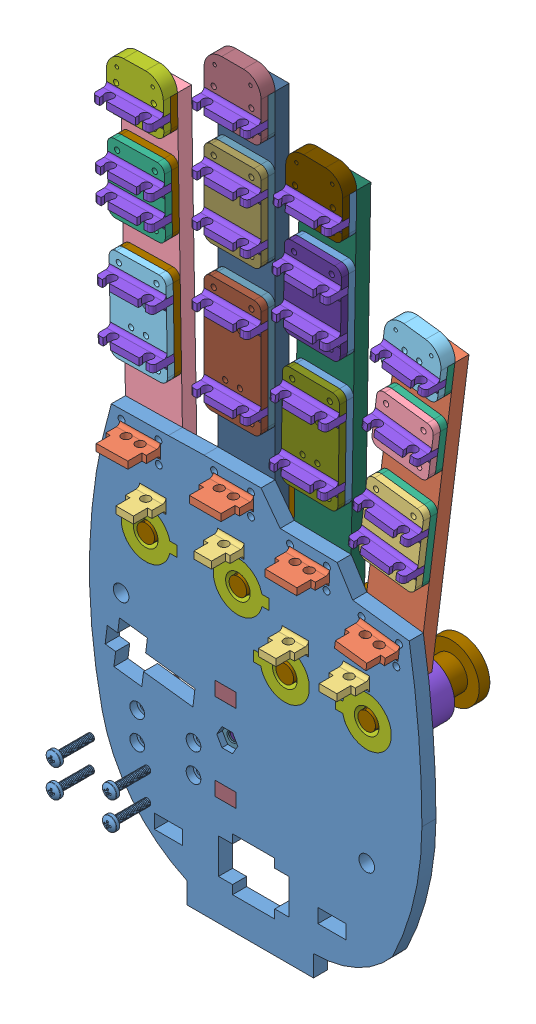
SolidWorks assembly palmUp_fingers_buttons_upPulley_servoBase, configuration Default. Lengths in mm.
Overall size (100.53 213.84 66.17).
198 component instances, 46 part files, 121 mates.
Components (placement in the parent):
- palmUp-1: palmUp [Default] at (29.1174 30.4931 80.2216) size (94.52 113.2 4)
- driverBaseFrame1-1: driverBaseFrame1 [Default] at (-2.9175 115.1932 80.2216) x (0.999847 0.017467 0) z (0.017467 -0.999847 0) size (11.5 12 4)
- driverBaseFrame1-2: driverBaseFrame1 [Default] at (23.5924 115.6931 80.2216) x (1 0 0) z (0 -1 0) size (11.5 12 4)
- driverBaseFrame1-3: driverBaseFrame1 [Default] at (45.1535 108.3901 80.2216) x (0.999848 -0.017452 0) z (-0.017452 -0.999848 0) size (11.5 12 4)
- driverBaseFrame1-4: driverBaseFrame1 [Default] at (65.1211 100.8452 80.2216) x (0.992117 -0.125312 0) z (-0.125312 -0.992117 0) size (11.5 12 4)
- driverBaseFrame2-1: driverBaseFrame2 [Default] at (-1948.2383 102.6443 -1374.6625) x (1 0 0) z (0 -1 0) size (7.5 12 4)
- driverBaseFrame2-2: driverBaseFrame2 [Default] at (1983.3157 100.6443 -1374.6625) x (-1 0 0) z (0 1 0) size (7.5 12 4)
- driverBaseFrame2-4: driverBaseFrame2 [Default] at (-1907.6963 87.8147 -1374.6625) x (1 0 0) z (0 -1 0) size (7.5 12 4)
- driverBaseFrame2-5: driverBaseFrame2 [Default] at (-1890.412 87.8147 -1374.6625) x (1 0 0) z (0 -1 0) size (7.5 12 4)
- index-1: index [Default] at (-52.494 173.2306 -0.0096) x (-0.999847 -0.017467 0) z (0 0 -1) size (16.2 99.16 12.01)
  - indexElastomer-1: indexElastomer [Default] at (-62.4059 -67.241 -80.2312) size (16.2 94.16 4)
  - indexPIP-1: indexPIP [Default] at (-62.4059 -42.8945 -84.2312) size (16.2 26.26 2)
  - indexMIP-1: indexMIP [Default] at (-62.4059 -8.6345 -84.2312) size (16.2 19.45 2)
  - indexDIP-1: indexDIP [Default] at (-62.4059 16.8205 -84.2312) size (16.2 14.95 4)
  - tubeDriver-6: tubeDriver [Default] at (-62.4059 20.8205 -80.2312) x (1 0 0) z (0 1 0) size (16.2 6 4)
  - tubeDriver-7: tubeDriver [Default] at (-62.4059 3.8205 -80.2312) x (1 0 0) z (0 1 0) size (16.2 6 4)
  - tubeDriver-8: tubeDriver [Default] at (-62.4059 -3.6345 -80.2312) x (1 0 0) z (0 1 0) size (16.2 6 4)
  - tubeDriver-9: tubeDriver [Default] at (-62.4059 -23.6345 -80.2312) x (1 0 0) z (0 1 0) size (16.2 6 4)
  - tubeDriver-10: tubeDriver [Default] at (-62.4059 -37.8945 -80.2312) x (1 0 0) z (0 1 0) size (16.2 6 4)
  - indexTube1-1: indexTube1 [Default] at (-49.2059 -21.6345 -86.4812) x (-0.964902 0 0.26261) z (0 -1 0) size (2.5 2.5 16.26) (hidden)
  - indexTube1-2: indexTube1 [Default] at (-59.4059 -21.6345 -86.4812) x (-0.775159 0 0.631766) z (0 -1 0) size (2.5 2.5 16.26) (hidden)
  - indexTube2-1: indexTube2 [Default] at (-49.2059 5.8205 -86.4812) x (0.360054 0 0.932932) z (0 -1 0) size (2.5 2.5 9.46) (hidden)
  - indexTube2-2: indexTube2 [Default] at (-59.4059 5.8205 -86.4812) x (-0.658969 0 -0.75217) z (0 -1 0) size (2.5 2.5 9.46) (hidden)
  - commonFingersTube-1: commonFingersTube [Default] at (-49.2059 22.8205 -86.4812) x (-0.856421 0 0.516277) z (0 -1 0) size (2.5 2.5 2) (hidden)
  - commonFingersTube-2: commonFingersTube [Default] at (-59.4059 22.8205 -86.4812) x (-0.999231 0 0.039215) z (0 -1 0) size (2.5 2.5 2) (hidden)
  - indexJointBase-1: indexJointBase [Default] at (-62.4059 -67.241 -82.2312) size (16.2 69.66 2)
- middle-1: middle [Default] at (34.8412 175.8995 -30.6566) size (16.2 113.14 12)
  - middleElastomer-1: middleElastomer [Default] at (-13.8237 -68.7065 106.8781) size (16.2 108.14 4)
  - middlePIP-1: middlePIP [Default] at (-13.8237 -44.2065 110.8781) size (16.2 33.21 2)
  - middleMIP-1: middleMIP [Default] at (-13.8237 -2.9965 110.8781) size (16.2 24.45 2)
  - middleDIP-1: middleDIP [Default] at (-5.7237 27.4535 110.8781) size (16.2 16.98 4)
  - tubeDriver-2: tubeDriver [Default] at (-13.8237 33.4535 110.8781) x (1 0 0) z (0 -1 0) size (16.2 6 4)
  - tubeDriver-3: tubeDriver [Default] at (-13.8237 16.4535 110.8781) x (1 0 0) z (0 -1 0) size (16.2 6 4)
  - tubeDriver-4: tubeDriver [Default] at (-13.8237 4.0035 110.8781) x (1 0 0) z (0 -1 0) size (16.2 6 4)
  - tubeDriver-5: tubeDriver [Default] at (-13.8237 -15.9965 110.8781) x (1 0 0) z (0 -1 0) size (16.2 6 4)
  - tubeDriver-6: tubeDriver [Default] at (-13.8237 -37.2065 110.8781) x (1 0 0) z (0 -1 0) size (16.2 6 4)
  - middleTube1-1: middleTube1 [Default] at (-10.8237 -39.2065 117.1281) x (1 0 0) z (0 1 0) size (2.5 2.5 23.21) (hidden)
  - middleTube1-2: middleTube1 [Default] at (-0.6237 -39.2065 117.1281) x (1 0 0) z (0 1 0) size (2.5 2.5 23.21) (hidden)
  - middleTube2-1: middleTube2 [Default] at (-10.8237 2.0035 117.1281) x (1 0 0) z (0 1 0) size (2.5 2.5 14.45) (hidden)
  - middleTube2-2: middleTube2 [Default] at (-0.6237 2.0035 117.1281) x (1 0 0) z (0 1 0) size (2.5 2.5 14.45) (hidden)
  - commonFingersTube-1: commonFingersTube [Default] at (-10.8237 31.4535 117.1281) x (1 0 0) z (0 1 0) size (2.5 2.5 2) (hidden)
  - commonFingersTube-2: commonFingersTube [Default] at (-0.6237 31.4535 117.1281) x (1 0 0) z (0 1 0) size (2.5 2.5 2) (hidden)
  - middleJointBase-1: middleJointBase [Default] at (-13.8237 -70.2065 110.8781) size (16.2 83.64 2)
- ring-1: ring [Default] at (23.5555 139.8292 -20.9472) x (-0.999848 0.017452 0) z (0 0 -1) size (16.2 107.96 12)
  - ringElastomer-1: ringElastomer [Default] at (-35.7683 -39.5573 -101.1688) size (16.2 102.96 4)
  - ringPIP-1: ringPIP [Default] at (-35.7683 -15.0573 -105.1688) size (16.2 29.14 2)
  - ringMIP-1: ringMIP [Default] at (-35.7683 22.0827 -105.1688) size (16.2 23.53 2)
  - ringDIP-1: ringDIP [Default] at (-19.5683 51.6077 -101.1688) x (-1 0 0) z (0 0 -1) size (16.2 16.8 4)
  - tubeDriver-6: tubeDriver [Default] at (-35.7683 55.6077 -101.1688) x (1 0 0) z (0 1 0) size (16.2 6 4)
  - tubeDriver-7: tubeDriver [Default] at (-35.7683 38.6077 -101.1688) x (1 0 0) z (0 1 0) size (16.2 6 4)
  - tubeDriver-8: tubeDriver [Default] at (-35.7683 27.0827 -101.1688) x (1 0 0) z (0 1 0) size (16.2 6 4)
  - tubeDriver-9: tubeDriver [Default] at (-35.7683 7.0827 -101.1688) x (1 0 0) z (0 1 0) size (16.2 6 4)
  - tubeDriver-10: tubeDriver [Default] at (-35.7683 -10.0573 -101.1688) x (1 0 0) z (0 1 0) size (16.2 6 4)
  - ringTube1-1: ringTube1 [Default] at (-22.5683 9.0827 -107.4188) x (1 0 0) z (0 -1 0) size (2.5 2.5 19.14) (hidden)
  - ringTube1-2: ringTube1 [Default] at (-32.7683 9.0827 -107.4188) x (1 0 0) z (0 -1 0) size (2.5 2.5 19.14) (hidden)
  - ringTube2-1: ringTube2 [Default] at (-22.5683 40.6077 -107.4188) x (1 0 0) z (0 -1 0) size (2.5 2.5 13.53) (hidden)
  - ringTube2-2: ringTube2 [Default] at (-32.7683 40.6077 -107.4188) x (1 0 0) z (0 -1 0) size (2.5 2.5 13.53) (hidden)
  - commonFingersTube-1: commonFingersTube [Default] at (-22.5683 57.6077 -107.4188) x (1 0 0) z (0 -1 0) size (2.5 2.5 2) (hidden)
  - commonFingersTube-2: commonFingersTube [Default] at (-32.7683 57.6077 -107.4188) x (-0.448476 0 -0.893795) z (0 -1 0) size (2.5 2.5 2) (hidden)
  - ringJointBase-1: ringJointBase [Default] at (-35.7683 -41.0573 -103.1688) size (16.2 78.46 2)
- pinky-1: pinky [Default] at (76.9532 164.3008 -0.0182) x (0.992117 -0.125312 0) z (0 0 1) size (16.2 89.09 12)
  - pinkyElastomer-1: pinkyElastomer [Default] at (-6.1366 -72.9381 76.2397) size (16.2 84.09 4)
  - pinkyPIP-1: pinkyPIP [Default] at (-6.1366 -48.4381 80.2397) size (16.2 21.74 2)
  - pinkyMIP-1: pinkyMIP [Default] at (-6.1366 -18.6981 80.2397) size (16.2 14.64 2)
  - pinkyDIP-1: pinkyDIP [Default] at (-6.1366 1.9469 80.2397) size (16.2 14.21 4)
  - tubeDriver-5: tubeDriver [Default] at (-6.1366 7.9469 80.2397) x (1 0 0) z (0 -1 0) size (16.2 6 4)
  - tubeDriver-7: tubeDriver [Default] at (-6.1366 -31.6981 80.2397) x (1 0 0) z (0 -1 0) size (16.2 6 4)
  - tubeDriver-8: tubeDriver [Default] at (-6.1366 -41.4381 80.2397) x (1 0 0) z (0 -1 0) size (16.2 6 4)
  - pinkyTube1-1: pinkyTube1 [Default] at (-3.1366 -43.4381 86.4897) x (1 0 0) z (0 1 0) size (2.5 2.5 11.74) (hidden)
  - pinkyTube1-2: pinkyTube1 [Default] at (7.0634 -43.4381 86.4897) x (1 0 0) z (0 1 0) size (2.5 2.5 11.74) (hidden)
  - tubeDriver-10: tubeDriver [Default] at (-6.1366 -10.3756 80.2397) x (1 0 0) z (0 -1 0) size (16.2 6 4)
  - commonFingersTube-1: commonFingersTube [Default] at (-3.1366 5.9469 86.4897) x (1 0 0) z (0 1 0) size (2.5 2.5 2) (hidden)
  - commonFingersTube-2: commonFingersTube [Default] at (7.0634 5.9469 86.4897) x (1 0 0) z (0 1 0) size (2.5 2.5 2) (hidden)
  - pinkyJointBase-1: pinkyJointBase [Default] at (-6.1366 -74.4381 80.2397) size (16.2 59.59 2)
  - commonFingersTube-3: commonFingersTube [Default] at (-3.1366 -12.3756 86.4897) x (1 0 0) z (0 1 0) size (2.5 2.5 2) (hidden)
  - commonFingersTube-4: commonFingersTube [Default] at (7.0634 -12.3756 86.4897) x (1 0 0) z (0 1 0) size (2.5 2.5 2) (hidden)
- buttonBase-1: buttonBase [Default] at (67.2648 77.3147 84.2216) x (0 -1 0) z (0 0 -1) size (16 16.84 9)
- buttonBase-2: buttonBase [Default] at (43.9805 77.3147 84.2216) x (0 -1 0) z (0 0 -1) size (16 16.84 9)
- buttonBase-3: buttonBase [Default] at (30.6388 92.1443 84.2216) x (0 1 0) z (0 0 -1) size (16 16.84 9)
- buttonBase-4: buttonBase [Default] at (4.4385 92.1443 84.2216) x (0 1 0) z (0 0 -1) size (16 16.84 9)
- buttonFrame-1: buttonFrame [Default] at (67.2648 77.3147 67.2216) x (-0.367754 -0.929923 0) z (0 0 1) size (16 16 8)
- buttonFrame-2: buttonFrame [Default] at (43.9805 77.3147 67.2216) x (-0.367754 -0.929923 0) z (0 0 1) size (16 16 8)
- buttonFrame-3: buttonFrame [Default] at (4.4385 92.1443 67.2216) x (-0.366273 -0.930508 0) z (0 0 1) size (16 16 8)
- buttonFrame-4: buttonFrame [Default] at (30.6388 92.1443 67.2216) x (-0.366273 -0.930508 0) z (0 0 1) size (16 16 8)
- buttonAxle-1: buttonAxle [Default] at (67.2648 77.3147 57.2216) size (16 16 27)
- buttonAxle-2: buttonAxle [Default] at (4.4385 92.1443 57.2216) size (16 16 27)
- buttonAxle-3: buttonAxle [Default] at (43.9805 77.3147 57.2216) x (-1 0 0) z (0 0 1) size (16 16 27)
- buttonAxle-4: buttonAxle [Default] at (30.6388 92.1443 57.2216) x (-1 0 0) z (0 0 1) size (16 16 27)
- parallel pin hardened_din-1: parallel pin hardened_din [Parallel Pin ISO 8734 - 2 x 14 - A - St] at (67.5898 69.8147 71.2178) x (0 1 0) z (-0.989175 0 -0.14674) size (14 2 2)
- parallel pin hardened_din-2: parallel pin hardened_din [Parallel Pin ISO 8734 - 2 x 14 - A - St] at (43.6555 69.8147 71.2178) x (0 1 0) z (-0.930242 0 0.366947) size (14 2 2)
- parallel pin hardened_din-3: parallel pin hardened_din [Parallel Pin ISO 8734 - 2 x 14 - A - St] at (4.7635 98.6443 71.2178) x (0 -1 0) z (0 0 1) size (14 2 2)
- parallel pin hardened_din-4: parallel pin hardened_din [Parallel Pin ISO 8734 - 2 x 14 - A - St] at (30.3138 98.6443 71.2178) x (0 -1 0) z (-0.297916 0 0.954592) size (14 2 2)
- Assem1-1: Assem1 [Default] at (68.1098 77.3321 69.8525) x (0.982823 0 0.184551) z (0 -1 0) size (9.07 23.24 9)
  - Spring Part-1: Spring Part [Default] at origin size (9 1 4.5)
  - Spring Part-7: Spring Part [Default] at (-0.0474 0.6138 0) x (0.988155 0.15346 0) z (0 0 -1) size (9 1 4.5)
  - Spring Part-8: Spring Part [Default] at (-0.0474 1.8415 0) x (0.988155 -0.15346 0) z (0 0 1) size (9 1 4.5)
  - Spring Part-9: Spring Part [Default] at (-0.0474 3.0692 0) x (0.988155 0.15346 0) z (0 0 -1) size (9 1 4.5)
  - Spring Part-10: Spring Part [Default] at (-0.0474 4.2969 0) x (0.988155 -0.15346 0) z (0 0 1) size (9 1 4.5)
  - Spring Part-11: Spring Part [Default] at (-0.0474 5.5246 0) x (0.988155 0.15346 0) z (0 0 -1) size (9 1 4.5)
  - Spring Part-12: Spring Part [Default] at (-0.0474 6.7522 0) x (0.988155 -0.15346 0) z (0 0 1) size (9 1 4.5) (hidden)
  - Spring Part-13: Spring Part [Default] at (-0.0474 7.9799 0) x (0.988155 0.15346 0) z (0 0 -1) size (9 1 4.5) (hidden)
  - Spring Part-14: Spring Part [Default] at (-0.0474 9.2076 0) x (0.988155 -0.15346 0) z (0 0 1) size (9 1 4.5) (hidden)
  - Spring Part-15: Spring Part [Default] at (-0.0474 10.4353 0) x (0.988155 0.15346 0) z (0 0 -1) size (9 1 4.5) (hidden)
  - Spring Part-16: Spring Part [Default] at (-0.0474 11.663 0) x (0.988155 -0.15346 0) z (0 0 1) size (9 1 4.5) (hidden)
  - Spring Part-17: Spring Part [Default] at (-0.0474 12.8906 0) x (0.988155 0.15346 0) z (0 0 -1) size (9 1 4.5) (hidden)
  - Spring Part-18: Spring Part [Default] at (-0.0474 14.1183 0) x (0.988155 -0.15346 0) z (0 0 1) size (9 1 4.5) (hidden)
  - Spring Part-19: Spring Part [Default] at (-0.0474 15.346 0) x (0.988155 0.15346 0) z (0 0 -1) size (9 1 4.5) (hidden)
  - Spring Part-20: Spring Part [Default] at (-0.0474 16.5737 0) x (0.988155 -0.15346 0) z (0 0 1) size (9 1 4.5) (hidden)
  - Spring Part-21: Spring Part [Default] at (-0.0474 17.8013 0) x (0.988155 0.15346 0) z (0 0 -1) size (9 1 4.5) (hidden)
  - Spring Part-22: Spring Part [Default] at (-0.0474 19.029 0) x (0.988155 -0.15346 0) z (0 0 1) size (9 1 4.5) (hidden)
  - Spring Part-23: Spring Part [Default] at (-0.0474 20.2567 0) x (0.988155 0.15346 0) z (0 0 -1) size (9 1 4.5) (hidden)
  - Spring Part-24: Spring Part [Default] at (-0.0474 21.4844 0) x (0.988155 -0.15346 0) z (0 0 1) size (9 1 4.5) (hidden)
  - Spring Part-25: Spring Part [Default] at (0 22.0982 0) x (1 0 0) z (0 0 -1) size (9 1 4.5) (hidden)
- Assem1-2: Assem1 [Default] at (43.2323 76.9505 75.7945) x (0.961864 0.191525 0.195284) z (-0.195284 0.980747 0) size (9.07 23.24 9)
  - Spring Part-1: Spring Part [Default] at origin size (9 1 4.5)
  - Spring Part-7: Spring Part [Default] at (-0.0474 0.6138 0) x (0.988155 0.15346 0) z (0 0 -1) size (9 1 4.5)
  - Spring Part-8: Spring Part [Default] at (-0.0474 1.8415 0) x (0.988155 -0.15346 0) z (0 0 1) size (9 1 4.5)
  - Spring Part-9: Spring Part [Default] at (-0.0474 3.0692 0) x (0.988155 0.15346 0) z (0 0 -1) size (9 1 4.5)
  - Spring Part-10: Spring Part [Default] at (-0.0474 4.2969 0) x (0.988155 -0.15346 0) z (0 0 1) size (9 1 4.5)
  - Spring Part-11: Spring Part [Default] at (-0.0474 5.5246 0) x (0.988155 0.15346 0) z (0 0 -1) size (9 1 4.5)
  - Spring Part-12: Spring Part [Default] at (-0.0474 6.7522 0) x (0.988155 -0.15346 0) z (0 0 1) size (9 1 4.5) (hidden)
  - Spring Part-13: Spring Part [Default] at (-0.0474 7.9799 0) x (0.988155 0.15346 0) z (0 0 -1) size (9 1 4.5) (hidden)
  - Spring Part-14: Spring Part [Default] at (-0.0474 9.2076 0) x (0.988155 -0.15346 0) z (0 0 1) size (9 1 4.5) (hidden)
  - Spring Part-15: Spring Part [Default] at (-0.0474 10.4353 0) x (0.988155 0.15346 0) z (0 0 -1) size (9 1 4.5) (hidden)
  - Spring Part-16: Spring Part [Default] at (-0.0474 11.663 0) x (0.988155 -0.15346 0) z (0 0 1) size (9 1 4.5) (hidden)
  - Spring Part-17: Spring Part [Default] at (-0.0474 12.8906 0) x (0.988155 0.15346 0) z (0 0 -1) size (9 1 4.5) (hidden)
  - Spring Part-18: Spring Part [Default] at (-0.0474 14.1183 0) x (0.988155 -0.15346 0) z (0 0 1) size (9 1 4.5) (hidden)
  - Spring Part-19: Spring Part [Default] at (-0.0474 15.346 0) x (0.988155 0.15346 0) z (0 0 -1) size (9 1 4.5) (hidden)
  - Spring Part-20: Spring Part [Default] at (-0.0474 16.5737 0) x (0.988155 -0.15346 0) z (0 0 1) size (9 1 4.5) (hidden)
  - Spring Part-21: Spring Part [Default] at (-0.0474 17.8013 0) x (0.988155 0.15346 0) z (0 0 -1) size (9 1 4.5) (hidden)
  - Spring Part-22: Spring Part [Default] at (-0.0474 19.029 0) x (0.988155 -0.15346 0) z (0 0 1) size (9 1 4.5) (hidden)
  - Spring Part-23: Spring Part [Default] at (-0.0474 20.2567 0) x (0.988155 0.15346 0) z (0 0 -1) size (9 1 4.5) (hidden)
  - Spring Part-24: Spring Part [Default] at (-0.0474 21.4844 0) x (0.988155 -0.15346 0) z (0 0 1) size (9 1 4.5) (hidden)
  - Spring Part-25: Spring Part [Default] at (0 22.0982 0) x (1 0 0) z (0 0 -1) size (9 1 4.5) (hidden)
- Assem1-3: Assem1 [Default] at (30.4884 91.6348 76.0217) x (1 0 0) z (0 1 0) size (9.07 23.24 9)
  - Spring Part-1: Spring Part [Default] at origin size (9 1 4.5)
  - Spring Part-7: Spring Part [Default] at (-0.0474 0.6138 0) x (0.988155 0.15346 0) z (0 0 -1) size (9 1 4.5)
  - Spring Part-8: Spring Part [Default] at (-0.0474 1.8415 0) x (0.988155 -0.15346 0) z (0 0 1) size (9 1 4.5)
  - Spring Part-9: Spring Part [Default] at (-0.0474 3.0692 0) x (0.988155 0.15346 0) z (0 0 -1) size (9 1 4.5)
  - Spring Part-10: Spring Part [Default] at (-0.0474 4.2969 0) x (0.988155 -0.15346 0) z (0 0 1) size (9 1 4.5)
  - Spring Part-11: Spring Part [Default] at (-0.0474 5.5246 0) x (0.988155 0.15346 0) z (0 0 -1) size (9 1 4.5)
  - Spring Part-12: Spring Part [Default] at (-0.0474 6.7522 0) x (0.988155 -0.15346 0) z (0 0 1) size (9 1 4.5) (hidden)
  - Spring Part-13: Spring Part [Default] at (-0.0474 7.9799 0) x (0.988155 0.15346 0) z (0 0 -1) size (9 1 4.5) (hidden)
  - Spring Part-14: Spring Part [Default] at (-0.0474 9.2076 0) x (0.988155 -0.15346 0) z (0 0 1) size (9 1 4.5) (hidden)
  - Spring Part-15: Spring Part [Default] at (-0.0474 10.4353 0) x (0.988155 0.15346 0) z (0 0 -1) size (9 1 4.5) (hidden)
  - Spring Part-16: Spring Part [Default] at (-0.0474 11.663 0) x (0.988155 -0.15346 0) z (0 0 1) size (9 1 4.5) (hidden)
  - Spring Part-17: Spring Part [Default] at (-0.0474 12.8906 0) x (0.988155 0.15346 0) z (0 0 -1) size (9 1 4.5) (hidden)
  - Spring Part-18: Spring Part [Default] at (-0.0474 14.1183 0) x (0.988155 -0.15346 0) z (0 0 1) size (9 1 4.5) (hidden)
  - Spring Part-19: Spring Part [Default] at (-0.0474 15.346 0) x (0.988155 0.15346 0) z (0 0 -1) size (9 1 4.5) (hidden)
  - Spring Part-20: Spring Part [Default] at (-0.0474 16.5737 0) x (0.988155 -0.15346 0) z (0 0 1) size (9 1 4.5) (hidden)
  - Spring Part-21: Spring Part [Default] at (-0.0474 17.8013 0) x (0.988155 0.15346 0) z (0 0 -1) size (9 1 4.5) (hidden)
  - Spring Part-22: Spring Part [Default] at (-0.0474 19.029 0) x (0.988155 -0.15346 0) z (0 0 1) size (9 1 4.5) (hidden)
  - Spring Part-23: Spring Part [Default] at (-0.0474 20.2567 0) x (0.988155 0.15346 0) z (0 0 -1) size (9 1 4.5) (hidden)
  - Spring Part-24: Spring Part [Default] at (-0.0474 21.4844 0) x (0.988155 -0.15346 0) z (0 0 1) size (9 1 4.5) (hidden)
  - Spring Part-25: Spring Part [Default] at (0 22.0982 0) x (1 0 0) z (0 0 -1) size (9 1 4.5) (hidden)
- Assem1-4: Assem1 [Default] at (3.643 90.6443 75.9726) x (1 0 0) z (0 1 0) size (9.07 23.24 9)
  - Spring Part-1: Spring Part [Default] at origin size (9 1 4.5)
  - Spring Part-7: Spring Part [Default] at (-0.0474 0.6138 0) x (0.988155 0.15346 0) z (0 0 -1) size (9 1 4.5)
  - Spring Part-8: Spring Part [Default] at (-0.0474 1.8415 0) x (0.988155 -0.15346 0) z (0 0 1) size (9 1 4.5)
  - Spring Part-9: Spring Part [Default] at (-0.0474 3.0692 0) x (0.988155 0.15346 0) z (0 0 -1) size (9 1 4.5)
  - Spring Part-10: Spring Part [Default] at (-0.0474 4.2969 0) x (0.988155 -0.15346 0) z (0 0 1) size (9 1 4.5)
  - Spring Part-11: Spring Part [Default] at (-0.0474 5.5246 0) x (0.988155 0.15346 0) z (0 0 -1) size (9 1 4.5)
  - Spring Part-12: Spring Part [Default] at (-0.0474 6.7522 0) x (0.988155 -0.15346 0) z (0 0 1) size (9 1 4.5) (hidden)
  - Spring Part-13: Spring Part [Default] at (-0.0474 7.9799 0) x (0.988155 0.15346 0) z (0 0 -1) size (9 1 4.5) (hidden)
  - Spring Part-14: Spring Part [Default] at (-0.0474 9.2076 0) x (0.988155 -0.15346 0) z (0 0 1) size (9 1 4.5) (hidden)
  - Spring Part-15: Spring Part [Default] at (-0.0474 10.4353 0) x (0.988155 0.15346 0) z (0 0 -1) size (9 1 4.5) (hidden)
  - Spring Part-16: Spring Part [Default] at (-0.0474 11.663 0) x (0.988155 -0.15346 0) z (0 0 1) size (9 1 4.5) (hidden)
  - Spring Part-17: Spring Part [Default] at (-0.0474 12.8906 0) x (0.988155 0.15346 0) z (0 0 -1) size (9 1 4.5) (hidden)
  - Spring Part-18: Spring Part [Default] at (-0.0474 14.1183 0) x (0.988155 -0.15346 0) z (0 0 1) size (9 1 4.5) (hidden)
  - Spring Part-19: Spring Part [Default] at (-0.0474 15.346 0) x (0.988155 0.15346 0) z (0 0 -1) size (9 1 4.5) (hidden)
  - Spring Part-20: Spring Part [Default] at (-0.0474 16.5737 0) x (0.988155 -0.15346 0) z (0 0 1) size (9 1 4.5) (hidden)
  - Spring Part-21: Spring Part [Default] at (-0.0474 17.8013 0) x (0.988155 0.15346 0) z (0 0 -1) size (9 1 4.5) (hidden)
  - Spring Part-22: Spring Part [Default] at (-0.0474 19.029 0) x (0.988155 -0.15346 0) z (0 0 1) size (9 1 4.5) (hidden)
  - Spring Part-23: Spring Part [Default] at (-0.0474 20.2567 0) x (0.988155 0.15346 0) z (0 0 -1) size (9 1 4.5) (hidden)
  - Spring Part-24: Spring Part [Default] at (-0.0474 21.4844 0) x (0.988155 -0.15346 0) z (0 0 1) size (9 1 4.5) (hidden)
  - Spring Part-25: Spring Part [Default] at (0 22.0982 0) x (1 0 0) z (0 0 -1) size (9 1 4.5) (hidden)
- SupportPulleyPalmUpAssem-1: SupportPulleyPalmUpAssem [Default] at (18.0404 39.4745 49.5054) size (10 28.63 11.6)
  - supportPulleyPalmUp2-1: supportPulleyPalmUp2 [Default] at (10.0404 13.9256 23.1162) size (7.5 28.63 2)
  - supportPulleyPalmUp-1: supportPulleyPalmUp [Default] at (12.0404 26.3656 34.7162) x (-1 0 0) z (0 -1 0) size (10 11.6 4)
  - supportPulleyPalmUp-2: supportPulleyPalmUp [Default] at (12.0404 1.7356 34.7162) x (-1 0 0) z (0 -1 0) size (10 11.6 4)
- hex nut style 1 gradeab_din-1: hex nut style 1 gradeab_din [Hexagon Nut ISO 4032 - M3 - D - S] at (27.442 52.7975 82.6216) x (0 1 0) z (0 0 1) size (5.5 6.35 2.4)
- plain washer 6902 type abc_din-1: plain washer 6902 type abc_din [DIN 6902-C3.2] at (28.0808 53.4001 80.2216) x (0 0 -1) z (0.195239 0.980756 0) size (0.8 7 7)
- pulley-1: pulley [Default] at (28.0808 53.4001 75.4216) x (0.991013 -0.133768 0) z (0 0 1) size (12 12 4)
- plain washer 6902 type abc_din-2: plain washer 6902 type abc_din [DIN 6902-C3.2] at (28.0808 53.4001 75.4216) x (0 0 -1) z (0.978291 0.207235 0) size (0.8 7 7)
- socket head cap screw 4762_din-1: socket head cap screw 4762_din [ISO 4762 M3 x 10 --- 10S] at (28.0808 53.4001 69.6216) x (0 0 1) z (-0.999894 -0.01457 0) size (13 5.5 5.5)
- baseHerkulex-1: baseHerkulex [Default] at (-4.9352 30.4931 54.2216) size (31 58.5 17.5)
- pan head cross recess screw_din-1: pan head cross recess screw_din [ISO 7045 - M2 x 10 - Z --- 10S] at (18.0174 47.3687 108.8216) x (0 0 -1) z (0.086476 0.996254 0) size (11.57 4 4)
- pan head cross recess screw_din-2: pan head cross recess screw_din [ISO 7045 - M2 x 10 - Z --- 10S] at (18.0174 39.3687 108.8216) x (0 0 -1) z (-0.029913 -0.999553 0) size (11.57 4 4)
- pan head cross recess screw_din-3: pan head cross recess screw_din [ISO 7045 - M2 x 10 - Z --- 10S] at (2.0174 39.3687 108.8216) x (0 0 -1) z (1 0 0) size (11.57 4 4)
- pan head cross recess screw_din-4: pan head cross recess screw_din [ISO 7045 - M2 x 10 - Z --- 10S] at (2.0174 47.3687 108.8216) x (0 0 -1) z (1 0 0) size (11.57 4 4)
- hex nut style 1 gradeab_din-2: hex nut style 1 gradeab_din [Hexagon Nut ISO 4032 - M2 - D - S] at (2.0174 39.3687 44.2216) x (0.792425 -0.60997 0) z (0 0 1) size (4 4.62 1.6)
- hex nut style 1 gradeab_din-3: hex nut style 1 gradeab_din [Hexagon Nut ISO 4032 - M2 - D - S] at (18.0174 47.3687 44.2216) x (0.098807 -0.995107 0) z (0 0 1) size (4 4.62 1.6)
- hex nut style 1 gradeab_din-4: hex nut style 1 gradeab_din [Hexagon Nut ISO 4032 - M2 - D - S] at (2.0174 47.3687 44.2216) size (4 4.62 1.6)
- hex nut style 1 gradeab_din-5: hex nut style 1 gradeab_din [Hexagon Nut ISO 4032 - M2 - D - S] at (18.0174 39.3687 44.2216) size (4 4.62 1.6)
- plasticSpacer-1: plasticSpacer [Default] at (2.0174 47.3687 73.2216) size (6 6 4)
- plasticSpacer-2: plasticSpacer [Default] at (18.0174 47.3687 73.2216) size (6 6 4)
- plasticSpacer-3: plasticSpacer [Default] at (18.0174 39.3687 73.2216) x (0.106039 0.994362 0) z (0 0 1) size (6 6 4)
- plasticSpacer-4: plasticSpacer [Default] at (2.0174 39.3687 73.2216) x (0.99764 -0.068656 0) z (0 0 1) size (6 6 4)
Mates (geometry in assembly coordinates):
- Coincident1: coincident anti-aligned: plane of palmUp-1 through (-1.6321 113.2154 84.2216) normal (-0.017467 0.999847 0); plane of driverBaseFrame1-1 through (-2.8826 113.1935 80.2216) normal (0.017467 -0.999847 0)
- Coincident2: coincident anti-aligned: plane of palmUp-1 through (7.3666 113.3726 84.2216) normal (-0.999847 -0.017467 0); plane of driverBaseFrame1-1 through (7.3666 113.3726 84.2216) normal (0.999847 0.017467 0)
- Coincident3: coincident aligned: plane of palmUp-1 through (143.3195 75.6611 80.2216) normal (0 0 -1); plane of driverBaseFrame1-1 through (-1.6328 113.2154 80.2216) normal (0 0 -1)
- Coincident4: coincident anti-aligned: plane of palmUp-1 through (24.8424 113.6931 84.2216) normal (0 1 0); plane of driverBaseFrame1-2 through (23.5924 113.6931 80.2216) normal (0 -1 0)
- Coincident5: coincident anti-aligned: plane of palmUp-1 through (24.8424 115.6931 84.2216) normal (1 0 0); plane of driverBaseFrame1-2 through (24.8424 113.6931 84.2216) normal (-1 0 0)
- Coincident6: coincident aligned: plane of palmUp-1 through (143.3195 75.6611 80.2216) normal (0 0 -1); plane of driverBaseFrame1-2 through (24.8424 113.6931 80.2216) normal (0 0 -1)
- Coincident7: coincident aligned: plane of palmUp-1 through (143.3195 75.6611 80.2216) normal (0 0 -1); plane of driverBaseFrame1-3 through (46.3684 106.3686 80.2216) normal (0 0 -1)
- Coincident8: coincident anti-aligned: plane of palmUp-1 through (54.952 108.2191 84.2216) normal (-0.017452 -0.999848 0); plane of driverBaseFrame1-3 through (45.1535 108.3901 80.2216) normal (0.017452 0.999848 0)
- Coincident12: coincident anti-aligned: plane of palmUp-1 through (46.4033 108.3683 84.2216) normal (0.999848 -0.017452 0); plane of driverBaseFrame1-3 through (46.3684 106.3686 84.2216) normal (-0.999848 0.017452 0)
- Coincident13: coincident anti-aligned: plane of palmUp-1 through (66.1107 98.7043 84.2216) normal (0.125312 0.992117 0); plane of driverBaseFrame1-4 through (64.8705 98.861 80.2216) normal (-0.125312 -0.992117 0)
- Coincident14: coincident aligned: plane of palmUp-1 through (143.3195 75.6611 80.2216) normal (0 0 -1); plane of driverBaseFrame1-4 through (66.1107 98.7043 80.2216) normal (0 0 -1)
- Coincident15: coincident anti-aligned: plane of palmUp-1 through (66.3613 100.6886 84.2216) normal (0.992117 -0.125312 0); plane of driverBaseFrame1-4 through (66.1107 98.7043 84.2216) normal (-0.992117 0.125312 0)
- Coincident16: coincident anti-aligned: plane of palmUp-1 through (3.9385 100.6443 84.2216) normal (0 1 0); plane of driverBaseFrame2-1 through (-1948.2383 100.6443 -1374.6625) normal (0 -1 0)
- Coincident17: coincident aligned: plane of palmUp-1 through (143.3195 75.6611 80.2216) normal (0 0 -1); plane of driverBaseFrame2-1 through (3.9385 100.6443 80.2216) normal (0 0 -1)
- Coincident18: coincident anti-aligned: plane of palmUp-1 through (3.9385 102.6443 84.2216) normal (1 0 0); plane of driverBaseFrame2-1 through (3.9385 100.6443 84.2216) normal (-1 0 0)
- Distance1: distance = 0 mm aligned: plane of palmUp-1 through (143.3195 75.6611 80.2216) normal (0 0 -1); plane of driverBaseFrame2-2 through (31.1388 102.6443 80.2216) normal (0 0 -1)
- Coincident20: coincident anti-aligned: plane of palmUp-1 through (31.1388 100.6443 84.2216) normal (-1 0 0); plane of driverBaseFrame2-2 through (31.1388 102.6443 84.2216) normal (1 0 0)
- Coincident21: coincident anti-aligned: plane of palmUp-1 through (26.1388 102.6443 84.2216) normal (0 -1 0); plane of driverBaseFrame2-2 through (1983.3157 102.6443 -1374.6625) normal (0 1 0)
- Coincident22: coincident anti-aligned: plane of palmUp-1 through (44.4805 85.8147 84.2216) normal (0 1 0); plane of driverBaseFrame2-4 through (-1907.6963 85.8147 -1374.6625) normal (0 -1 0)
- Coincident23: coincident aligned: plane of palmUp-1 through (143.3195 75.6611 80.2216) normal (0 0 -1); plane of driverBaseFrame2-4 through (44.4805 85.8147 80.2216) normal (0 0 -1)
- Coincident24: coincident anti-aligned: plane of palmUp-1 through (49.4805 85.8147 84.2216) normal (-1 0 0); plane of driverBaseFrame2-4 through (49.4805 85.8147 84.2216) normal (1 0 0)
- Coincident25: coincident anti-aligned: plane of palmUp-1 through (61.7648 85.8147 84.2216) normal (0 1 0); plane of driverBaseFrame2-5 through (-1890.412 85.8147 -1374.6625) normal (0 -1 0)
- Coincident26: coincident aligned: plane of palmUp-1 through (143.3195 75.6611 80.2216) normal (0 0 -1); plane of driverBaseFrame2-5 through (61.7648 85.8147 80.2216) normal (0 0 -1)
- Coincident27: coincident anti-aligned: plane of palmUp-1 through (61.7648 87.8147 84.2216) normal (1 0 0); plane of driverBaseFrame2-5 through (61.7648 85.8147 84.2216) normal (-1 0 0)
- Concentric1: concentric anti-aligned: cylinder of palmUp-1 through (8.0553 116.8851 84.2216) axis (0 0 -1) radius 0.975; cylinder of index-1/indexElastomer-1 through (8.0553 116.8851 76.2216) axis (0 0 1) radius 0.5
- Concentric2: concentric anti-aligned: cylinder of palmUp-1 through (8.1601 110.886 84.2216) axis (0 0 -1) radius 0.975; cylinder of index-1/indexElastomer-1 through (8.1601 110.886 76.2216) axis (0 0 1) radius 0.5
- Coincident28: coincident anti-aligned: plane of palmUp-1 through (143.3195 75.6611 80.2216) normal (0 0 -1); plane of index-1/indexElastomer-1 through (11.0769 107.0899 80.2216) normal (0 0 1)
- Concentric3: concentric aligned: cylinder of palmUp-1 through (23.8674 111.1931 84.2216) axis (0 0 -1) radius 0.975; cylinder of middle-1/middleElastomer-1 through (23.8674 111.1931 80.2216) axis (0 0 -1) radius 0.52
- Concentric4: concentric aligned: circle of palmUp-1; circle of middle-1/middleElastomer-1
- Coincident29: coincident anti-aligned: plane of palmUp-1 through (143.3195 75.6611 80.2216) normal (0 0 -1); plane of middle-1/middleElastomer-1 through (21.0174 107.1931 80.2216) normal (0 0 1)
- Concentric5: concentric aligned: circle of palmUp-1; cylinder of ring-1/ringElastomer-1 through (45.3499 103.886 76.2216) axis (0 0 1) radius 0.5
- Concentric6: concentric anti-aligned: cylinder of palmUp-1 through (45.4546 109.8851 84.2216) axis (0 0 -1) radius 0.975; cylinder of ring-1/ringElastomer-1 through (45.4546 109.8851 76.2216) axis (0 0 1) radius 0.5
- Coincident30: coincident anti-aligned: plane of palmUp-1 through (143.3195 75.6611 80.2216) normal (0 0 -1); plane of ring-1/ringElastomer-1 through (58.628 99.6536 80.2216) normal (0 0 1)
- Concentric7: concentric aligned: cylinder of palmUp-1 through (65.0537 96.318 84.2216) axis (0 0 -1) radius 0.975; cylinder of pinky-1/pinkyElastomer-1 through (65.0537 96.318 80.2216) axis (0 0 -1) radius 0.52
- Concentric8: concentric anti-aligned: cylinder of palmUp-1 through (65.8055 102.2707 84.2216) axis (0 0 -1) radius 0.975; circle of pinky-1/pinkyElastomer-1
- Coincident31: coincident anti-aligned: plane of palmUp-1 through (143.3195 75.6611 80.2216) normal (0 0 -1); plane of pinky-1/pinkyElastomer-1 through (61.7249 92.7066 80.2216) normal (0 0 1)
- Concentric9: concentric anti-aligned: cylinder of palmUp-1 through (67.2648 77.3147 84.2216) axis (0 0 -1) radius 7; cylinder of buttonBase-1 through (67.2648 77.3147 80.2216) axis (0 0 1) radius 7
- Coincident32: coincident: moEndPointRef_w of palmUp-1; plane of buttonBase-1 through (60.4274 75.8147 80.2216) normal (0 -1 0)
- Coincident40: coincident anti-aligned: plane of palmUp-1 through (143.3195 75.6611 80.2216) normal (0 0 -1); plane of buttonBase-1 through (67.2648 77.3147 80.2216) normal (0 0 1)
- Concentric10: concentric anti-aligned: cylinder of palmUp-1 through (43.9805 77.3147 84.2216) axis (0 0 -1) radius 7; cylinder of buttonBase-2 through (43.9805 77.3147 80.2216) axis (0 0 1) radius 7
- Coincident34: coincident anti-aligned: plane of palmUp-1 through (35.1431 75.8147 84.2216) normal (0 1 0); plane of buttonBase-2 through (37.1431 75.8147 80.2216) normal (0 -1 0)
- Coincident41: coincident anti-aligned: plane of palmUp-1 through (143.3195 75.6611 80.2216) normal (0 0 -1); plane of buttonBase-2 through (43.9805 77.3147 80.2216) normal (0 0 1)
- Concentric11: concentric anti-aligned: cylinder of palmUp-1 through (30.6388 92.1443 84.2216) axis (0 0 -1) radius 7; cylinder of buttonBase-3 through (30.6388 92.1443 80.2216) axis (0 0 1) radius 7
- Coincident37: coincident anti-aligned: plane of palmUp-1 through (39.4762 90.6443 84.2216) normal (0 1 0); plane of buttonBase-3 through (38.497 90.6443 80.2216) normal (0 -1 0)
- Coincident42: coincident anti-aligned: plane of palmUp-1 through (143.3195 75.6611 80.2216) normal (0 0 -1); plane of buttonBase-3 through (30.6388 92.1443 80.2216) normal (0 0 1)
- Concentric13: concentric anti-aligned: cylinder of palmUp-1 through (4.4385 92.1443 84.2216) axis (0 0 -1) radius 7; cylinder of buttonBase-4 through (4.4385 92.1443 80.2216) axis (0 0 1) radius 7
- Coincident39: coincident anti-aligned: plane of palmUp-1 through (11.2759 93.6443 84.2216) normal (0 -1 0); plane of buttonBase-4 through (11.2759 93.6443 80.2216) normal (0 1 0)
- Coincident43: coincident anti-aligned: plane of palmUp-1 through (143.3195 75.6611 80.2216) normal (0 0 -1); plane of buttonBase-4 through (4.4385 92.1443 80.2216) normal (0 0 1)
- Concentric14: concentric anti-aligned: cylinder of buttonBase-1 through (67.2648 77.3147 75.2216) axis (0 0 1) radius 5; cylinder of buttonFrame-1 through (67.2648 77.3147 75.2216) axis (0 0 -1) radius 5
- Coincident44: coincident aligned: plane of buttonBase-1 through (63.4238 70.2971 76.2216) normal (0.877201 -0.480124 0); plane of buttonFrame-1 through (63.4238 70.2971 72.7216) normal (0.877201 -0.480124 0)
- Coincident60: coincident anti-aligned: plane of buttonBase-1 through (67.2648 77.3147 75.2216) normal (0 0 -1); plane of buttonFrame-1 through (67.2648 77.3147 75.2216) normal (0 0 1)
- Concentric15: concentric anti-aligned: cylinder of buttonBase-2 through (43.9805 77.3147 75.2216) axis (0 0 1) radius 5; cylinder of buttonFrame-2 through (43.9805 77.3147 75.2216) axis (0 0 -1) radius 5
- Coincident46: coincident: line of buttonBase-2 through (41.5799 72.9287 77.2216) axis (-0.480124 -0.877201 0); plane of buttonFrame-2 through (40.1395 70.2971 72.7216) normal (0.877201 -0.480124 0)
- Coincident61: coincident anti-aligned: plane of buttonBase-2 through (43.9805 77.3147 75.2216) normal (0 0 -1); plane of buttonFrame-2 through (43.9805 77.3147 75.2216) normal (0 0 1)
- Concentric16: concentric anti-aligned: cylinder of buttonBase-3 through (30.6388 92.1443 75.2216) axis (0 0 1) radius 5; cylinder of buttonFrame-4 through (30.6388 92.1443 75.2216) axis (0 0 -1) radius 5
- Parallel1: parallel aligned: plane of buttonBase-4 through (0.6087 85.1206 76.2216) normal (0.877964 -0.478727 0); plane of buttonFrame-4 through (26.809 85.1206 72.7216) normal (0.877964 -0.478727 0)
- Coincident63: coincident anti-aligned: plane of buttonBase-4 through (4.4385 92.1443 75.2216) normal (0 0 -1); plane of buttonFrame-4 through (30.6388 92.1443 75.2216) normal (0 0 1)
- Concentric17: concentric anti-aligned: cylinder of buttonBase-4 through (4.4385 92.1443 75.2216) axis (0 0 1) radius 5; cylinder of buttonFrame-3 through (4.4385 92.1443 75.2216) axis (0 0 -1) radius 5
- Coincident50: coincident aligned: plane of buttonBase-4 through (0.6087 85.1206 76.2216) normal (0.877964 -0.478727 0); plane of buttonFrame-3 through (0.6087 85.1206 72.7216) normal (0.877964 -0.478727 0)
- Coincident62: coincident anti-aligned: plane of buttonBase-4 through (4.4385 92.1443 75.2216) normal (0 0 -1); plane of buttonFrame-3 through (4.4385 92.1443 75.2216) normal (0 0 1)
- Concentric18: concentric aligned: cylinder of buttonFrame-1 through (67.2648 77.3147 75.2216) axis (0 0 -1) radius 5; cylinder of buttonAxle-1 through (67.2648 77.3147 74.2216) axis (0 0 -1) radius 4.675
- Distance6: distance = 7 mm anti-aligned: plane of buttonAxle-1 through (67.2648 77.3147 74.2216) normal (0 0 1); plane of buttonFrame-1 through (67.2648 77.3147 67.2216) normal (0 0 -1)
- Concentric19: concentric aligned: cylinder of buttonFrame-2 through (43.9805 77.3147 75.2216) axis (0 0 -1) radius 5; cylinder of buttonAxle-3 through (43.9805 77.3147 74.2216) axis (0 0 -1) radius 4.675
- Distance7: distance = 7 mm anti-aligned: plane of buttonFrame-2 through (43.9805 77.3147 67.2216) normal (0 0 -1); plane of buttonAxle-3 through (43.9805 77.3147 74.2216) normal (0 0 1)
- Concentric20: concentric aligned: cylinder of buttonFrame-4 through (30.6388 92.1443 75.2216) axis (0 0 -1) radius 5; cylinder of buttonAxle-4 through (30.6388 92.1443 74.2216) axis (0 0 -1) radius 4.675
- Distance8: distance = 7 mm anti-aligned: plane of buttonFrame-4 through (30.6388 92.1443 67.2216) normal (0 0 -1); plane of buttonAxle-4 through (30.6388 92.1443 74.2216) normal (0 0 1)
- Concentric21: concentric aligned: cylinder of buttonFrame-3 through (4.4385 92.1443 75.2216) axis (0 0 -1) radius 5; cylinder of buttonAxle-2 through (4.4385 92.1443 74.2216) axis (0 0 -1) radius 4.675
- Distance9: distance = 7 mm anti-aligned: plane of buttonFrame-3 through (4.4385 92.1443 67.2216) normal (0 0 -1); plane of buttonAxle-2 through (4.4385 92.1443 74.2216) normal (0 0 1)
- Concentric22: concentric anti-aligned: cylinder of buttonAxle-1 through (67.5898 69.8147 71.2178) axis (0 1 0) radius 1.225; cylinder of parallel pin hardened_din-1 through (67.5898 63.4647 71.2178) axis (0 -1 0) radius 1
- Distance10: distance = 6 mm aligned: plane of parallel pin hardened_din-1 through (67.7227 69.8147 70.3214) normal (0 -1 0); plane of buttonBase-1 through (60.4274 75.8147 80.2216) normal (0 -1 0)
- Concentric23: concentric aligned: cylinder of buttonAxle-3 through (43.6555 84.8147 71.2178) axis (0 -1 0) radius 1.225; cylinder of parallel pin hardened_din-2 through (43.6555 63.4647 71.2178) axis (0 -1 0) radius 1
- Distance11: distance = 8 mm anti-aligned: plane of parallel pin hardened_din-2 through (43.6555 83.8147 71.2178) normal (0 1 0); plane of buttonBase-2 through (37.1431 75.8147 80.2216) normal (0 -1 0)
- Concentric24: concentric anti-aligned: cylinder of buttonAxle-4 through (30.3138 99.6443 71.2178) axis (0 -1 0) radius 1.225; cylinder of parallel pin hardened_din-4 through (30.3138 104.9943 71.2178) axis (0 1 0) radius 1
- Distance12: distance = 6 mm aligned: plane of parallel pin hardened_din-4 through (30.3138 84.6443 71.2178) normal (0 -1 0); plane of buttonBase-3 through (38.497 90.6443 80.2216) normal (0 -1 0)
- Concentric25: concentric aligned: cylinder of buttonAxle-2 through (4.7635 84.6443 71.2178) axis (0 1 0) radius 1.225; cylinder of parallel pin hardened_din-3 through (4.7635 104.9943 71.2178) axis (0 1 0) radius 1
- Distance13: distance = 6 mm aligned: plane of parallel pin hardened_din-3 through (4.7635 84.6443 71.2178) normal (0 -1 0); plane of buttonBase-4 through (12.2966 90.6443 80.2216) normal (0 -1 0)
- Parallel2: parallel anti-aligned: plane of buttonBase-1 through (60.4274 75.8147 80.2216) normal (0 -1 0); plane of Assem1-1/Spring Part-11 through (70.8151 77.3321 76.6062) normal (0 1 0)
- Parallel3: parallel: line of buttonBase-2 through (36.1224 75.8147 75.2216) axis (0 0 1); plane of Assem1-2/Spring Part-1 through (47.0797 77.7166 76.5756) normal (-0.195284 0.980747 0)
- Parallel4: parallel anti-aligned: plane of buttonBase-3 through (38.497 90.6443 80.2216) normal (0 -1 0); plane of Assem1-3/Spring Part-1 through (34.4884 91.6348 76.0217) normal (0 1 0)
- Coincident59: coincident anti-aligned: plane of buttonBase-4 through (12.2966 90.6443 80.2216) normal (0 -1 0); plane of Assem1-4/Spring Part-1 through (7.643 90.6443 75.9726) normal (0 1 0)
- Coincident64: coincident anti-aligned: plane of palmUp-1 through (30.0808 37.2101 84.2216) normal (0 1 0); plane of SupportPulleyPalmUpAssem-1/supportPulleyPalmUp-2 through (30.0808 37.2101 84.2216) normal (0 -1 0)
- Coincident65: coincident anti-aligned: plane of palmUp-1 through (24.0808 37.2101 84.2216) normal (1 0 0); plane of SupportPulleyPalmUpAssem-1/supportPulleyPalmUp-2 through (24.0808 37.2101 84.2216) normal (-1 0 0)
- Coincident67: coincident anti-aligned: plane of palmUp-1 through (29.1174 50.1994 84.2216) normal (-0.866025 0.5 0); plane of hex nut style 1 gradeab_din-1 through (29.0297 50.0475 80.2216) normal (0.866025 -0.5 0)
- Coincident68: coincident anti-aligned: plane of palmUp-1 through (30.6174 52.7975 84.2216) normal (-0.866025 -0.5 0); plane of hex nut style 1 gradeab_din-1 through (30.6174 52.7975 80.2216) normal (0.866025 0.5 0)
- Coincident69: coincident aligned: plane of palmUp-1 through (143.3195 75.6611 80.2216) normal (0 0 -1); plane of hex nut style 1 gradeab_din-1 through (24.2666 52.7975 80.2216) normal (0 0 -1)
- Concentric26: concentric anti-aligned: cylinder of SupportPulleyPalmUpAssem-1/supportPulleyPalmUp2-1 through (28.0808 53.4001 74.6216) axis (0 0 -1) radius 1.5; cylinder of plain washer 6902 type abc_din-1 through (28.0808 53.4001 79.4216) axis (0 0 1) radius 1.6
- Coincident70: coincident anti-aligned: plane of hex nut style 1 gradeab_din-1 through (24.2666 52.7975 80.2216) normal (0 0 -1); plane of plain washer 6902 type abc_din-1 through (28.0808 53.4001 80.2216) normal (0 0 1)
- Concentric27: concentric aligned: cylinder of SupportPulleyPalmUpAssem-1/supportPulleyPalmUp2-1 through (28.0808 53.4001 74.6216) axis (0 0 -1) radius 1.5; cylinder of pulley-1 through (28.0808 53.4001 77.4216) axis (0 0 -1) radius 1.5
- Coincident71: coincident anti-aligned: plane of plain washer 6902 type abc_din-1 through (28.0808 53.4001 79.4216) normal (0 0 -1); plane of pulley-1 through (28.0808 53.4001 79.4216) normal (0 0 1)
- Concentric28: concentric anti-aligned: cylinder of pulley-1 through (28.0808 53.4001 77.4216) axis (0 0 -1) radius 1.5; cylinder of plain washer 6902 type abc_din-2 through (28.0808 53.4001 74.6216) axis (0 0 1) radius 1.6
- Coincident72: coincident anti-aligned: plane of pulley-1 through (28.0808 53.4001 75.4216) normal (0 0 -1); plane of plain washer 6902 type abc_din-2 through (28.0808 53.4001 75.4216) normal (0 0 1)
- Coincident73: coincident anti-aligned: plane of SupportPulleyPalmUpAssem-1/supportPulleyPalmUp2-1 through (28.0808 53.4001 74.6216) normal (0 0 1); plane of plain washer 6902 type abc_din-2 through (28.0808 53.4001 74.6216) normal (0 0 -1)
- Coincident74: coincident aligned: cylinder of SupportPulleyPalmUpAssem-1/supportPulleyPalmUp2-1 through (28.0808 53.4001 74.6216) axis (0 0 -1) radius 1.5; circle of socket head cap screw 4762_din-1
- Coincident75: coincident anti-aligned: plane of SupportPulleyPalmUpAssem-1/supportPulleyPalmUp2-1 through (28.0808 53.4001 72.6216) normal (0 0 -1); plane of socket head cap screw 4762_din-1 through (28.0407 56.1498 72.6216) normal (0 0 1)
- Concentric29: concentric anti-aligned: cylinder of palmUp-1 through (18.0174 39.3687 84.2216) axis (0 0 -1) radius 1.225; cylinder of baseHerkulex-1 through (18.0174 39.3687 68.2216) axis (0 0 1) radius 1.5
- Concentric31: concentric anti-aligned: cylinder of palmUp-1 through (2.0174 39.3687 84.2216) axis (0 0 -1) radius 1.225; cylinder of baseHerkulex-1 through (2.0174 39.3687 68.2216) axis (0 0 1) radius 1.5
- Distance14: distance = 20 mm anti-aligned: plane of baseHerkulex-1 through (-4.9352 30.4931 60.2216) normal (0 0 1); plane of palmUp-1 through (143.3195 75.6611 80.2216) normal (0 0 -1)
- Concentric32: concentric aligned: circle of palmUp-1; circle of pan head cross recess screw_din-1
- Distance15: distance = 25 mm anti-aligned: plane of palmUp-1 through (18.0174 47.3687 82.2216) normal (0 0 1); plane of pan head cross recess screw_din-1 through (17.0212 47.4552 107.2216) normal (0 0 -1)
- Concentric33: concentric aligned: cylinder of palmUp-1 through (18.0174 39.3687 82.2216) axis (0 0 1) radius 2.1; circle of pan head cross recess screw_din-2
- Distance16: distance = 25 mm anti-aligned: plane of pan head cross recess screw_din-2 through (19.017 39.3388 107.2216) normal (0 0 -1); plane of palmUp-1 through (18.0174 39.3687 82.2216) normal (0 0 1)
- Concentric34: concentric aligned: cylinder of palmUp-1 through (2.0174 39.3687 82.2216) axis (0 0 1) radius 2.1; circle of pan head cross recess screw_din-3
- Distance17: distance = 25 mm anti-aligned: plane of palmUp-1 through (2.0174 39.3687 82.2216) normal (0 0 1); plane of pan head cross recess screw_din-3 through (2.0174 40.3687 107.2216) normal (0 0 -1)
- Concentric35: concentric aligned: cylinder of palmUp-1 through (2.0174 47.3687 82.2216) axis (0 0 1) radius 2.1; circle of pan head cross recess screw_din-4
- Distance18: distance = 25 mm anti-aligned: plane of palmUp-1 through (2.0174 47.3687 82.2216) normal (0 0 1); plane of pan head cross recess screw_din-4 through (2.0174 48.3687 107.2216) normal (0 0 -1)
- Concentric36: concentric anti-aligned: cylinder of baseHerkulex-1 through (18.0174 47.3687 68.2216) axis (0 0 1) radius 1.5; circle of hex nut style 1 gradeab_din-3
- Distance19: distance = 10 mm anti-aligned: plane of hex nut style 1 gradeab_din-3 through (20.3155 47.5969 44.2216) normal (0 0 1); plane of baseHerkulex-1 through (-4.9352 30.4931 54.2216) normal (0 0 -1)
- Concentric37: concentric aligned: cylinder of baseHerkulex-1 through (2.0174 47.3687 68.2216) axis (0 0 1) radius 1.5; circle of hex nut style 1 gradeab_din-4
- Distance20: distance = 10 mm anti-aligned: plane of baseHerkulex-1 through (-4.9352 30.4931 54.2216) normal (0 0 -1); plane of hex nut style 1 gradeab_din-4 through (2.0174 49.6781 44.2216) normal (0 0 1)
- Concentric38: concentric aligned: cylinder of baseHerkulex-1 through (18.0174 39.3687 68.2216) axis (0 0 1) radius 1.5; circle of hex nut style 1 gradeab_din-5
- Distance21: distance = 10 mm anti-aligned: plane of baseHerkulex-1 through (-4.9352 30.4931 54.2216) normal (0 0 -1); plane of hex nut style 1 gradeab_din-5 through (18.0174 41.6781 44.2216) normal (0 0 1)
- Concentric39: concentric aligned: cylinder of baseHerkulex-1 through (2.0174 39.3687 68.2216) axis (0 0 1) radius 1.5; circle of hex nut style 1 gradeab_din-2
- Distance22: distance = 10 mm anti-aligned: plane of baseHerkulex-1 through (-4.9352 30.4931 54.2216) normal (0 0 -1); plane of hex nut style 1 gradeab_din-2 through (3.4261 41.1987 44.2216) normal (0 0 1)
- Concentric40: concentric aligned: cylinder of palmUp-1 through (2.0174 47.3687 84.2216) axis (0 0 -1) radius 1.225; cylinder of plasticSpacer-1 through (2.0174 47.3687 77.2216) axis (0 0 -1) radius 2
- Distance23: distance = 3 mm anti-aligned: plane of palmUp-1 through (143.3195 75.6611 80.2216) normal (0 0 -1); plane of plasticSpacer-1 through (2.0174 47.3687 77.2216) normal (0 0 1)
- Concentric41: concentric aligned: cylinder of palmUp-1 through (18.0174 47.3687 84.2216) axis (0 0 -1) radius 1.225; cylinder of plasticSpacer-2 through (18.0174 47.3687 77.2216) axis (0 0 -1) radius 2
- Distance24: distance = 3 mm anti-aligned: plane of palmUp-1 through (143.3195 75.6611 80.2216) normal (0 0 -1); plane of plasticSpacer-2 through (18.0174 47.3687 77.2216) normal (0 0 1)
- Concentric42: concentric: cylinder of palmUp-1 through (18.0174 39.3687 84.2216) axis (0 0 -1) radius 1.225; cylinder of plasticSpacer-3 through (18.0174 39.3687 77.2216) axis (0 0 -1) radius 2
- Distance25: distance = 3 mm anti-aligned: plane of plasticSpacer-3 through (18.0174 39.3687 77.2216) normal (0 0 1); plane of palmUp-1 through (143.3195 75.6611 80.2216) normal (0 0 -1)
- Concentric43: concentric: cylinder of palmUp-1 through (2.0174 39.3687 84.2216) axis (0 0 -1) radius 1.225; cylinder of plasticSpacer-4 through (2.0174 39.3687 77.2216) axis (0 0 -1) radius 2
- Distance26: distance = 3 mm anti-aligned: plane of palmUp-1 through (143.3195 75.6611 80.2216) normal (0 0 -1); plane of plasticSpacer-4 through (2.0174 39.3687 77.2216) normal (0 0 1)
